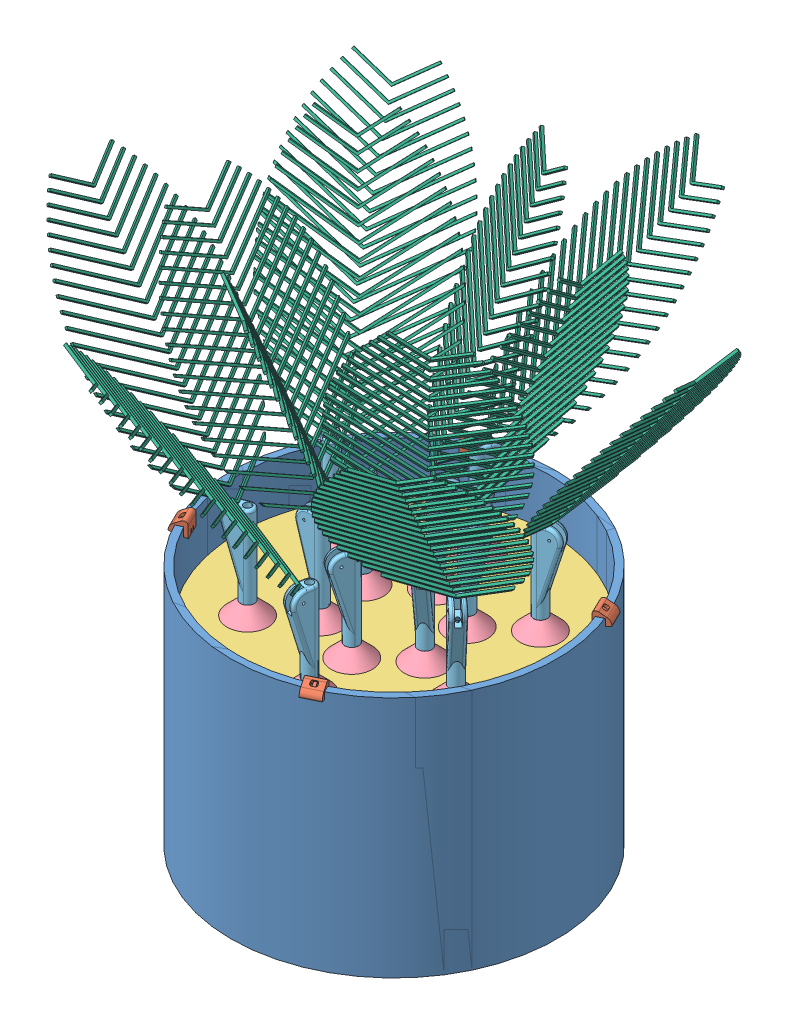
SolidWorks assembly full assembly, configuration Default. Lengths in mm.
Overall size (369.99 401.31 418.54).
43 component instances, 6 part files, 11 mates.
Components (placement in the parent):
- Flower pot-1: Flower pot [Default] at (-0.2603 -85.8815 -1.9133) size (238.76 177.8 238.76)
- Flower pot-2: Flower pot [Default] at (-0.2603 -85.8815 -1.9133) size (238.76 177.8 238.76)
- Sensor mount 2-1: Sensor mount 2 [Default] at (40.0082 84.8199 102.8236) x (0.899424 0 -0.437076) z (-0.113124 0.965926 -0.232788) size (12.7 11.68 9.9)
- Sensor mount 2-2: Sensor mount 2 [Default] at (104.4766 84.8199 -42.1819) x (-0.437076 0 -0.899424) z (-0.232788 0.965926 0.113124) size (12.7 11.68 9.9)
- Sensor mount 2-3: Sensor mount 2 [Default] at (-40.5289 84.8199 -106.6503) x (-0.899424 0 0.437076) z (0.113124 0.965926 0.232788) size (12.7 11.68 9.9)
- Sensor mount 2-4: Sensor mount 2 [Default] at (-104.9973 84.8199 38.3552) x (0.437076 0 0.899424) z (0.232788 0.965926 -0.113124) size (12.7 11.68 9.9)
- leaf base pot-1: leaf base pot [Default] at (-0.2603 50.0891 -1.9133) x (0.985117 0 -0.171883) z (0.171883 0 0.985117) size (228.6 5.08 228.6)
- cone-1: cone [Default] at (58.2 65.1691 -50.7891) x (-0.837169 0 -0.546944) z (0 1 0) size (30 30 10)
- cone-2: cone [Default] at (-13.3578 65.1691 -76.9793) x (-0.892252 0 0.451538) z (0 1 0) size (30 30 10)
- cone-3: cone [Default] at (-71.8181 65.1691 -28.1035) x (-0.055083 0 0.998482) z (0 1 0) size (30 30 10)
- cone-4: cone [Default] at (-58.7206 65.1691 46.9624) x (0.837169 0 0.546944) z (0 1 0) size (30 30 10)
- cone-5: cone [Default] at (12.8372 65.1691 73.1526) x (0.892252 0 -0.451538) z (0 1 0) size (30 30 10)
- cone-6: cone [Default] at (71.2975 65.1691 24.2769) x (0.055083 0 -0.998482) z (0 1 0) size (30 30 10)
- cone-7: cone [Default] at (28.9698 65.1691 -26.3512) x (-0.837169 0 -0.546944) z (0 1 0) size (30 30 10)
- cone-8: cone [Default] at (-6.8091 65.1691 -39.4463) x (-0.892252 0 0.451538) z (0 1 0) size (30 30 10)
- cone-9: cone [Default] at (-36.0392 65.1691 -15.0084) x (-0.055083 0 0.998482) z (0 1 0) size (30 30 10)
- cone-10: cone [Default] at (-29.4904 65.1691 22.5245) x (0.837169 0 0.546944) z (0 1 0) size (30 30 10)
- cone-11: cone [Default] at (6.2884 65.1691 35.6196) x (0.892252 0 -0.451538) z (0 1 0) size (30 30 10)
- cone-12: cone [Default] at (35.5186 65.1691 11.1818) x (0.055083 0 -0.998482) z (0 1 0) size (30 30 10)
- ThickStrawStem2-1: ThickStrawStem2 [Default] at (71.2975 95.1691 24.2769) x (0.773994 0 0.633192) z (0 -1 0) size (19 10 60)
- ThickStrawStem2-2: ThickStrawStem2 [Default] at (58.2 95.1691 -50.7891) x (0.935358 0 -0.353703) z (0 -1 0) size (19 10 60)
- ThickStrawStem2-3: ThickStrawStem2 [Default] at (-13.3578 95.1691 -76.9793) x (0.161364 0 -0.986895) z (0 -1 0) size (19 10 60)
- ThickStrawStem2-4: ThickStrawStem2 [Default] at (-71.8181 95.1691 -28.1035) x (-0.773994 0 -0.633192) z (0 -1 0) size (19 10 60)
- ThickStrawStem2-5: ThickStrawStem2 [Default] at (-58.7206 95.1691 46.9624) x (-0.935358 0 0.353703) z (0 -1 0) size (19 10 60)
- ThickStrawStem2-6: ThickStrawStem2 [Default] at (12.8372 95.1691 73.1526) x (-0.161364 0 0.986895) z (0 -1 0) size (19 10 60)
- assemblyleafmedium-1: assemblyleafmedium [Default] at (17.9672 136.88 93.4089) x (-0.879812 -0.044515 -0.473232) z (0.314517 -0.801 -0.509389) size (113.79 1.91 198.23)
- assemblyleafmedium-2: assemblyleafmedium [Default] at (-73.698 136.88 61.5333) x (-0.030075 -0.044515 -0.998556) z (0.598403 -0.801 0.017685) size (113.79 1.91 198.23)
- assemblyleafmedium-3: assemblyleafmedium [Default] at (-91.9256 136.88 -33.7889) x (0.849737 -0.044515 -0.525324) z (0.283885 -0.801 0.527075) size (113.79 1.91 198.23)
- assemblyleafmedium-4: assemblyleafmedium [Default] at (-18.4878 136.88 -97.2356) x (0.879812 -0.044515 0.473232) z (-0.314517 -0.801 0.509389) size (113.79 1.91 198.23)
- assemblyleafmedium-5: assemblyleafmedium [Default] at (73.1774 136.88 -65.36) x (0.030075 -0.044515 0.998556) z (-0.598403 -0.801 -0.017685) size (113.79 1.91 198.23)
- assemblyleafmedium-6: assemblyleafmedium [Default] at (91.4049 136.88 29.9623) x (-0.849737 -0.044515 0.525324) z (-0.283885 -0.801 -0.527075) size (113.79 1.91 198.23)
- assemblyleafmedium-7: assemblyleafmedium [Default] at (33.1114 137.1963 -40.6948) x (0.010507 0.114662 0.993349) z (-0.358605 -0.926892 0.110784) size (113.79 1.91 198.23)
- ThickStrawStem2-7: ThickStrawStem2 [Default] at (-29.4904 95.1691 22.5245) x (-0.997717 0 0.067533) z (0 -1 0) size (19 10 60)
- ThickStrawStem2-8: ThickStrawStem2 [Default] at (-36.0392 95.1691 -15.0084) x (-0.557343 0 -0.830282) z (0 -1 0) size (19 10 60)
- ThickStrawStem2-9: ThickStrawStem2 [Default] at (-6.8091 95.1691 -39.4463) x (0.440374 0 -0.897815) z (0 -1 0) size (19 10 60)
- ThickStrawStem2-10: ThickStrawStem2 [Default] at (28.9698 95.1691 -26.3512) x (0.997717 0 -0.067533) z (0 -1 0) size (19 10 60)
- ThickStrawStem2-11: ThickStrawStem2 [Default] at (35.5186 95.1691 11.1818) x (0.557343 0 0.830282) z (0 -1 0) size (19 10 60)
- ThickStrawStem2-12: ThickStrawStem2 [Default] at (6.2884 95.1691 35.6196) x (-0.440374 0 0.897815) z (0 -1 0) size (19 10 60)
- assemblyleafmedium-8: assemblyleafmedium [Default] at (-17.1602 137.1963 -50.2048) x (0.865519 0.114662 0.487575) z (-0.083361 -0.926892 0.365953) size (113.79 1.91 198.23)
- assemblyleafmedium-9: assemblyleafmedium [Default] at (-50.5319 137.1963 -11.4234) x (0.855012 0.114662 -0.505774) z (0.275244 -0.926892 0.255169) size (113.79 1.91 198.23)
- assemblyleafmedium-10: assemblyleafmedium [Default] at (-33.632 137.1963 36.8681) x (-0.010507 0.114662 -0.993349) z (0.358605 -0.926892 -0.110784) size (113.79 1.91 198.23)
- assemblyleafmedium-11: assemblyleafmedium [Default] at (16.6396 137.1963 46.3781) x (-0.865519 0.114662 -0.487575) z (0.083361 -0.926892 -0.365953) size (113.79 1.91 198.23)
- assemblyleafmedium-12: assemblyleafmedium [Default] at (50.0113 137.1963 7.5967) x (-0.855012 0.114662 0.505774) z (-0.275244 -0.926892 -0.255169) size (113.79 1.91 198.23)
Mates (geometry in assembly coordinates):
- Coincident2: coincident: circle of Flower pot-1; circle of Flower pot-2
- Coincident4: coincident anti-aligned: plane of Flower pot-1 through (-0.2603 91.9185 -1.9133) normal (0 1 0); plane of Sensor mount 2-1 through (65.0361 91.9185 96.2131) normal (0 -1 0)
- Coincident5: coincident: circle of Flower pot-1; moEndPointRef_w of Sensor mount 2-1
- Coincident6: coincident: circle of Flower pot-1; point of Sensor mount 2-1
- Concentric1: concentric aligned: cylinder of Flower pot-1 through (-0.2603 91.9185 -1.9133) axis (0 -1 0) radius 114.3; cylinder of leaf base pot-1 through (-0.2603 55.1691 -1.9133) axis (0 -1 0) radius 114.3
- Coincident7: coincident aligned: circle of cone-1; circle of leaf base pot-1
- Coincident8: coincident aligned: circle of leaf base pot-1; circle of cone-7
- Coincident9: coincident anti-aligned: circle of cone-6; circle of ThickStrawStem2-1
- Coincident14: coincident: moEndPointRef_w of ThickStrawStem2-6; point of assemblyleafmedium-1
- Coincident17: coincident anti-aligned: circle of cone-10; circle of ThickStrawStem2-7
- Coincident18: coincident: point of assemblyleafmedium-7; moEndPointRef_w of ThickStrawStem2-10
